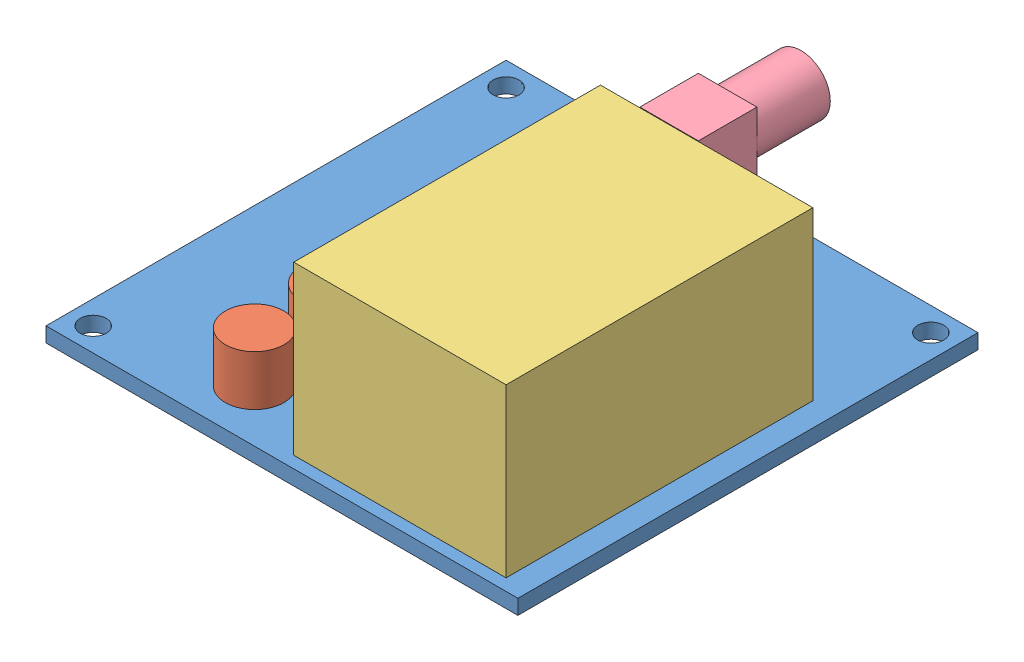
SolidWorks assembly board, configuration Default. Lengths in mm.
Overall size (50.8 21.1 56.13).
5 component instances, 4 part files, 8 mates.
Components (placement in the parent):
- pcb-1: pcb [Default] at (15.9017 26.2809 40.2207) size (50.8 1.6 49.53)
- cap-1: cap [Default] at (7.3184 27.8809 56.3321) size (6.3 5.4 6.3)
- cap-2: cap [Default] at (7.2054 27.8809 48.1368) size (6.3 5.4 6.3)
- moteino-1: moteino [Default] at (27.3317 27.8809 47.2057) size (22.86 18 33.02)
- sma-1: sma [Default] at (15.6517 27.8809 19.9057) size (6.3 13.53 14.2)
Mates (geometry in assembly coordinates):
- Coincident1: coincident anti-aligned: plane of pcb-1 through (15.9017 27.8809 40.2207) normal (0 1 0); plane of moteino-1 through (27.3317 27.8809 47.2057) normal (0 -1 0)
- Coincident2: coincident anti-aligned: plane of pcb-1 through (15.9017 27.8809 40.2207) normal (0 1 0); plane of cap-2 through (7.2054 27.8809 51.1459) normal (0 -1 0)
- Coincident3: coincident anti-aligned: plane of pcb-1 through (15.9017 27.8809 40.2207) normal (0 1 0); plane of cap-1 through (7.3184 27.8809 59.3412) normal (0 -1 0)
- Distance3: distance = 1.27 mm: line of moteino-1 through (15.9017 27.8809 63.7157) axis (1 0 0); line of pcb-1 through (-9.4983 27.8809 64.9857) axis (1 0 0)
- Distance4: distance = 2.54 mm: line of moteino-1 through (38.7617 27.8809 63.7157) axis (0 0 -1); line of pcb-1 through (41.3017 27.8809 64.9857) axis (0 0 -1)
- Coincident5: coincident: plane of pcb-1 through (15.9017 27.8809 40.2207) normal (0 1 0); plane of sma-1 through (15.2417 27.8809 20.5063) normal (0 -1 0)
- Distance5: distance = 22 mm: line of sma-1 through (12.5017 27.8809 17.2404) axis (0 0 1); line of pcb-1 through (-9.4983 27.8809 15.4557) axis (0 0 1)
- Distance6: distance = 1.3 mm: line of sma-1 through (18.8017 27.8809 16.7557) axis (-1 0 0); line of pcb-1 through (41.3017 27.8809 15.4557) axis (-1 0 0)
